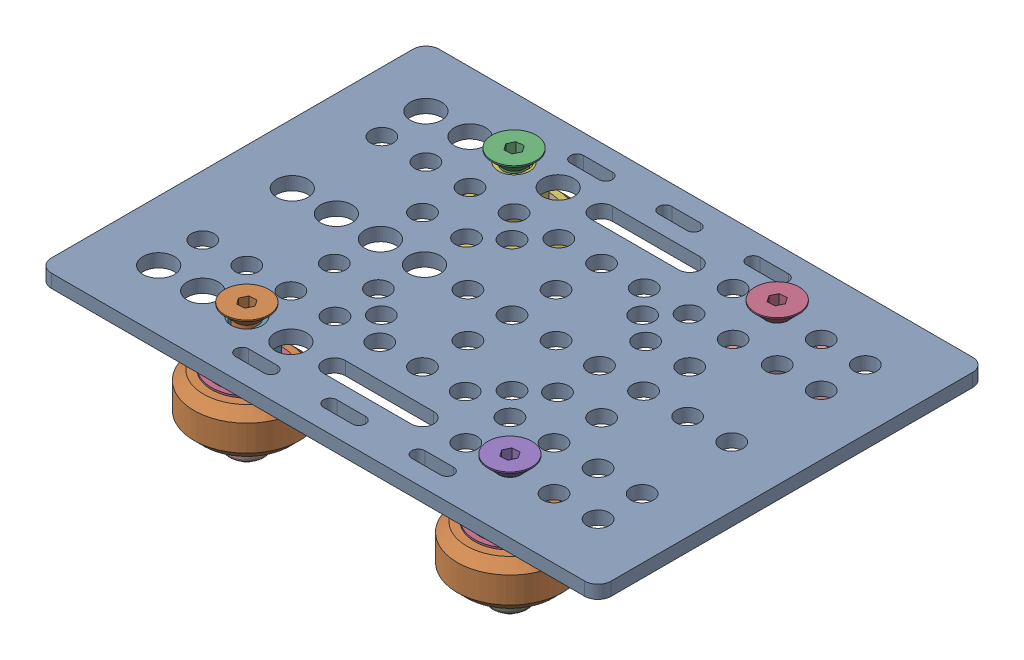
SolidWorks assembly plateau_haut, configuration Default. Lengths in mm.
Overall size (127 30 88.17).
37 component instances, 9 part files, 40 mates.
Components (placement in the parent):
- User Library-GANTRY-PLATE-127-88-1: User Library-GANTRY-PLATE-127-88 [Default] at (-22.0656 -4.5834 13.7385) size (127 3 88)
- item_8000118_vis_fhc_m5x30_din_7991_details_3-1: item_8000118_vis_fhc_m5x30_din_7991_details_3 [Default] at (-51.9156 -1.5834 44.0585) x (0.566406 0 0.824126) z (0 1 0) size (10 10 30)
- item_8000118_vis_fhc_m5x30_din_7991_details_3-2: item_8000118_vis_fhc_m5x30_din_7991_details_3 [Default] at (-51.9156 -1.5834 -16.5815) x (0.566406 0 0.824126) z (0 1 0) size (10 10 30)
- item_8000118_vis_fhc_m5x30_din_7991_details_3-3: item_8000118_vis_fhc_m5x30_din_7991_details_3 [Default] at (7.7844 -1.5834 -16.5815) x (0.566406 0 0.824126) z (0 1 0) size (10 10 30)
- item_8000118_vis_fhc_m5x30_din_7991_details_3-4: item_8000118_vis_fhc_m5x30_din_7991_details_3 [Default] at (7.7844 -1.5834 44.0585) x (0.566406 0 0.824126) z (0 1 0) size (10 10 30)
- User Library-ENTR-EXC-HEX10-6-1: User Library-ENTR-EXC-HEX10-6 [Défaut] at (-51.9156 -4.5834 -16.5815) x (0.999657 0 0.026177) z (0.026177 0 -0.999657) size (11.55 8.5 10)
- User Library-ENTR-EXC-HEX10-6-2: User Library-ENTR-EXC-HEX10-6 [Défaut] at (-51.9156 -4.5834 44.0585) x (-0.99999 0 -0.004471) z (-0.004471 0 0.99999) size (11.55 8.5 10)
- entretoise-1: entretoise [Default] at (7.7844 -10.5834 -16.5815) x (1 0 0) z (0 1 0) size (10 10 6)
- entretoise-2: entretoise [Default] at (7.7844 -10.5834 44.0585) x (1 0 0) z (0 1 0) size (10 10 6)
- rondelle-1: rondelle [Default] at (-51.9156 -11.5834 -16.5815) x (0.930418 0 -0.366501) z (0 1 0) size (8 8 1)
- rondelle-2: rondelle [Default] at (-51.9156 -11.5834 44.0585) x (1 0 0) z (0 1 0) size (8 8 1)
- rondelle-3: rondelle [Default] at (7.7844 -11.5834 -16.5815) x (1 0 0) z (0 1 0) size (8 8 1)
- rondelle-4: rondelle [Default] at (7.7844 -11.5834 44.0585) x (1 0 0) z (0 1 0) size (8 8 1)
- User Library-WHL-VSLOT-DLRN-1: User Library-WHL-VSLOT-DLRN [Straight] at (-51.9156 -17.0834 44.0585) x (0.999713 0 0.023977) z (-0.023977 0 0.999713) size (23.9 11 23.9)
  - User Library-WHL-VSLOT-DLRN_Solid V Wheel-1: User Library-WHL-VSLOT-DLRN_Solid V Wheel [Default] x (0 -1 0) z (0 0 1) size (10.2 23.9 23.9)
  - User Library-WHL-VSLOT-DLRN_Ball Bearing 5 x 16 x 5-1: User Library-WHL-VSLOT-DLRN_Ball Bearing 5 x 16 x 5 [Default] at (0 -3 0) x (0 -1 0) z (0.990411 0 0.138155) size (5 16 16)
  - User Library-WHL-VSLOT-DLRN_Ball Bearing 5 x 16 x 5-2: User Library-WHL-VSLOT-DLRN_Ball Bearing 5 x 16 x 5 [Default] at (0 3 0) x (0 1 0) z (-0.887666 0 -0.460488) size (5 16 16)
  - User Library-WHL-VSLOT-DLRN_Precision Shim 10 x 5 x 1-1: User Library-WHL-VSLOT-DLRN_Precision Shim 10 x 5 x 1 [Default] at (0 -0.5 0) x (0.977063 0 -0.212952) z (0.212952 0 0.977063) size (10 1 10)
- User Library-WHL-VSLOT-DLRN-2: User Library-WHL-VSLOT-DLRN [Straight] at (-51.9156 -17.0834 -16.5815) x (0.998521 0 0.054369) z (-0.054369 0 0.998521) size (23.9 11 23.9)
  - User Library-WHL-VSLOT-DLRN_Solid V Wheel-1: User Library-WHL-VSLOT-DLRN_Solid V Wheel [Default] x (0 -1 0) z (0 0 1) size (10.2 23.9 23.9)
  - User Library-WHL-VSLOT-DLRN_Ball Bearing 5 x 16 x 5-1: User Library-WHL-VSLOT-DLRN_Ball Bearing 5 x 16 x 5 [Default] at (0 -3 0) x (0 -1 0) z (0.990411 0 0.138155) size (5 16 16)
  - User Library-WHL-VSLOT-DLRN_Ball Bearing 5 x 16 x 5-2: User Library-WHL-VSLOT-DLRN_Ball Bearing 5 x 16 x 5 [Default] at (0 3 0) x (0 1 0) z (-0.887666 0 -0.460488) size (5 16 16)
  - User Library-WHL-VSLOT-DLRN_Precision Shim 10 x 5 x 1-1: User Library-WHL-VSLOT-DLRN_Precision Shim 10 x 5 x 1 [Default] at (0 -0.5 0) x (0.977063 0 -0.212952) z (0.212952 0 0.977063) size (10 1 10)
- User Library-WHL-VSLOT-DLRN-3: User Library-WHL-VSLOT-DLRN [Straight] at (7.7844 -17.0834 -16.5815) x (0.990448 0 -0.137886) z (0.137886 0 0.990448) size (23.9 11 23.9)
  - User Library-WHL-VSLOT-DLRN_Solid V Wheel-1: User Library-WHL-VSLOT-DLRN_Solid V Wheel [Default] x (0 -1 0) z (0 0 1) size (10.2 23.9 23.9)
  - User Library-WHL-VSLOT-DLRN_Ball Bearing 5 x 16 x 5-1: User Library-WHL-VSLOT-DLRN_Ball Bearing 5 x 16 x 5 [Default] at (0 -3 0) x (0 -1 0) z (0.990411 0 0.138155) size (5 16 16)
  - User Library-WHL-VSLOT-DLRN_Ball Bearing 5 x 16 x 5-2: User Library-WHL-VSLOT-DLRN_Ball Bearing 5 x 16 x 5 [Default] at (0 3 0) x (0 1 0) z (-0.887666 0 -0.460488) size (5 16 16)
  - User Library-WHL-VSLOT-DLRN_Precision Shim 10 x 5 x 1-1: User Library-WHL-VSLOT-DLRN_Precision Shim 10 x 5 x 1 [Default] at (0 -0.5 0) x (0.977063 0 -0.212952) z (0.212952 0 0.977063) size (10 1 10)
- User Library-WHL-VSLOT-DLRN-5: User Library-WHL-VSLOT-DLRN [Straight] at (7.7844 -17.0834 44.0585) x (0.984743 0 -0.174014) z (0.174014 0 0.984743) size (23.9 11 23.9)
  - User Library-WHL-VSLOT-DLRN_Solid V Wheel-1: User Library-WHL-VSLOT-DLRN_Solid V Wheel [Default] x (0 -1 0) z (0 0 1) size (10.2 23.9 23.9)
  - User Library-WHL-VSLOT-DLRN_Ball Bearing 5 x 16 x 5-1: User Library-WHL-VSLOT-DLRN_Ball Bearing 5 x 16 x 5 [Default] at (0 -3 0) x (0 -1 0) z (0.990411 0 0.138155) size (5 16 16)
  - User Library-WHL-VSLOT-DLRN_Ball Bearing 5 x 16 x 5-2: User Library-WHL-VSLOT-DLRN_Ball Bearing 5 x 16 x 5 [Default] at (0 3 0) x (0 1 0) z (-0.887666 0 -0.460488) size (5 16 16)
  - User Library-WHL-VSLOT-DLRN_Precision Shim 10 x 5 x 1-1: User Library-WHL-VSLOT-DLRN_Precision Shim 10 x 5 x 1 [Default] at (0 -0.5 0) x (0.977063 0 -0.212952) z (0.212952 0 0.977063) size (10 1 10)
- ecrou_frein2-1: ecrou_frein2 [Default] at (-51.9156 -22.5834 -16.5815) x (0 -1 0) z (0 0 1) size (5 9.24 8.1)
- ecrou_frein2-2: ecrou_frein2 [Default] at (7.7844 -22.5834 -16.5815) x (0 -1 0) z (0 0 1) size (5 9.24 8.1)
- ecrou_frein2-3: ecrou_frein2 [Default] at (-51.9156 -22.5834 44.0585) x (0 -1 0) z (0 0 1) size (5 9.24 8.1)
- ecrou_frein2-4: ecrou_frein2 [Default] at (7.7844 -22.5834 44.0585) x (0 -1 0) z (0 0 1) size (5 9.24 8.1)
Mates (geometry in assembly coordinates):
- Concentric1: concentric anti-aligned: cylinder of User Library-GANTRY-PLATE-127-88-1 through (-51.9156 -1.5834 44.0585) axis (0 -1 0) radius 3.55; cylinder of item_8000118_vis_fhc_m5x30_din_7991_details_3-1 through (-51.9156 -13.7834 44.0585) axis (0 1 0) radius 2.5
- Tangent2: tangent: plane of User Library-GANTRY-PLATE-127-88-1 through (-82.5656 -1.5834 54.7385) normal (0 1 0); circle of item_8000118_vis_fhc_m5x30_din_7991_details_3-1
- Concentric3: concentric anti-aligned: cylinder of User Library-GANTRY-PLATE-127-88-1 through (-51.9156 -1.5834 -16.5815) axis (0 -1 0) radius 3.55; cylinder of item_8000118_vis_fhc_m5x30_din_7991_details_3-2 through (-51.9156 -13.7834 -16.5815) axis (0 1 0) radius 2.5
- Coincident1: coincident anti-aligned: plane of User Library-GANTRY-PLATE-127-88-1 through (-82.5656 -1.5834 54.7385) normal (0 1 0); circle of item_8000118_vis_fhc_m5x30_din_7991_details_3-2
- Concentric4: concentric anti-aligned: cylinder of User Library-GANTRY-PLATE-127-88-1 through (7.7844 -1.5834 -16.5815) axis (0 -1 0) radius 2.55; cylinder of item_8000118_vis_fhc_m5x30_din_7991_details_3-3 through (7.7844 -13.7834 -16.5815) axis (0 1 0) radius 2.5
- Coincident2: coincident anti-aligned: plane of User Library-GANTRY-PLATE-127-88-1 through (-82.5656 -1.5834 54.7385) normal (0 1 0); circle of item_8000118_vis_fhc_m5x30_din_7991_details_3-3
- Concentric5: concentric anti-aligned: cylinder of User Library-GANTRY-PLATE-127-88-1 through (7.7844 -1.5834 44.0585) axis (0 -1 0) radius 2.55; cylinder of item_8000118_vis_fhc_m5x30_din_7991_details_3-4 through (7.7844 -13.7834 44.0585) axis (0 1 0) radius 2.5
- Coincident3: coincident anti-aligned: plane of User Library-GANTRY-PLATE-127-88-1 through (-82.5656 -1.5834 54.7385) normal (0 1 0); circle of item_8000118_vis_fhc_m5x30_din_7991_details_3-4
- Concentric6: concentric aligned: cylinder of User Library-GANTRY-PLATE-127-88-1 through (-51.9156 -1.5834 -16.5815) axis (0 -1 0) radius 3.55; cylinder of User Library-ENTR-EXC-HEX10-6-1 through (-51.9156 -2.0834 -16.5815) axis (0 -1 0) radius 3.555
- Coincident4: coincident anti-aligned: plane of User Library-GANTRY-PLATE-127-88-1 through (-82.5656 -4.5834 54.7385) normal (0 -1 0); plane of User Library-ENTR-EXC-HEX10-6-1 through (-51.9156 -4.5834 -16.5815) normal (0 1 0)
- Concentric7: concentric aligned: cylinder of User Library-GANTRY-PLATE-127-88-1 through (-51.9156 -1.5834 44.0585) axis (0 -1 0) radius 3.55; cylinder of User Library-ENTR-EXC-HEX10-6-2 through (-51.9156 -2.0834 44.0585) axis (0 -1 0) radius 3.555
- Coincident5: coincident anti-aligned: plane of User Library-GANTRY-PLATE-127-88-1 through (-82.5656 -4.5834 54.7385) normal (0 -1 0); plane of User Library-ENTR-EXC-HEX10-6-2 through (-51.9156 -4.5834 44.0585) normal (0 1 0)
- Concentric8: concentric anti-aligned: cylinder of item_8000118_vis_fhc_m5x30_din_7991_details_3-3 through (7.7844 -13.7834 -16.5815) axis (0 1 0) radius 2.5; cylinder of entretoise-1 through (7.7844 -4.5834 -16.5815) axis (0 -1 0) radius 2.5
- Coincident6: coincident anti-aligned: plane of User Library-GANTRY-PLATE-127-88-1 through (-82.5656 -4.5834 54.7385) normal (0 -1 0); plane of entretoise-1 through (7.7844 -4.5834 -16.5815) normal (0 1 0)
- Concentric9: concentric anti-aligned: cylinder of item_8000118_vis_fhc_m5x30_din_7991_details_3-4 through (7.7844 -13.7834 44.0585) axis (0 1 0) radius 2.5; cylinder of entretoise-2 through (7.7844 -4.5834 44.0585) axis (0 -1 0) radius 2.5
- Coincident7: coincident anti-aligned: plane of User Library-GANTRY-PLATE-127-88-1 through (-82.5656 -4.5834 54.7385) normal (0 -1 0); plane of entretoise-2 through (7.7844 -4.5834 44.0585) normal (0 1 0)
- Concentric10: concentric anti-aligned: cylinder of item_8000118_vis_fhc_m5x30_din_7991_details_3-2 through (-51.9156 -13.7834 -16.5815) axis (0 1 0) radius 2.5; cylinder of rondelle-1 through (-51.9156 -10.5834 -16.5815) axis (0 -1 0) radius 2.5
- Concentric11: concentric anti-aligned: cylinder of item_8000118_vis_fhc_m5x30_din_7991_details_3-1 through (-51.9156 -13.7834 44.0585) axis (0 1 0) radius 2.5; cylinder of rondelle-2 through (-51.9156 -10.5834 44.0585) axis (0 -1 0) radius 2.5
- Concentric12: concentric anti-aligned: cylinder of item_8000118_vis_fhc_m5x30_din_7991_details_3-4 through (7.7844 -13.7834 44.0585) axis (0 1 0) radius 2.5; cylinder of rondelle-4 through (7.7844 -10.5834 44.0585) axis (0 -1 0) radius 2.5
- Concentric13: concentric anti-aligned: cylinder of item_8000118_vis_fhc_m5x30_din_7991_details_3-3 through (7.7844 -13.7834 -16.5815) axis (0 1 0) radius 2.5; cylinder of rondelle-3 through (7.7844 -10.5834 -16.5815) axis (0 -1 0) radius 2.5
- Coincident8: coincident anti-aligned: plane of User Library-ENTR-EXC-HEX10-6-1 through (-51.9156 -10.5834 -16.5815) normal (0 -1 0); plane of rondelle-1 through (-51.9156 -10.5834 -16.5815) normal (0 1 0)
- Coincident9: coincident anti-aligned: plane of User Library-ENTR-EXC-HEX10-6-2 through (-51.9156 -10.5834 44.0585) normal (0 -1 0); plane of rondelle-2 through (-51.9156 -10.5834 44.0585) normal (0 1 0)
- Coincident10: coincident anti-aligned: plane of entretoise-1 through (7.7844 -10.5834 -16.5815) normal (0 -1 0); plane of rondelle-3 through (7.7844 -10.5834 -16.5815) normal (0 1 0)
- Coincident11: coincident anti-aligned: plane of entretoise-2 through (7.7844 -10.5834 44.0585) normal (0 -1 0); plane of rondelle-4 through (7.7844 -10.5834 44.0585) normal (0 1 0)
- Concentric14: concentric anti-aligned: cylinder of item_8000118_vis_fhc_m5x30_din_7991_details_3-2 through (-51.9156 -13.7834 -16.5815) axis (0 1 0) radius 2.5; cylinder of User Library-WHL-VSLOT-DLRN-2/User Library-WHL-VSLOT-DLRN_Ball Bearing 5 x 16 x 5-1 through (-51.9156 -20.0834 -16.5815) axis (0 -1 0) radius 2.5
- Concentric15: concentric anti-aligned: cylinder of item_8000118_vis_fhc_m5x30_din_7991_details_3-1 through (-51.9156 -13.7834 44.0585) axis (0 1 0) radius 2.5; cylinder of User Library-WHL-VSLOT-DLRN-1/User Library-WHL-VSLOT-DLRN_Ball Bearing 5 x 16 x 5-1 through (-51.9156 -20.0834 44.0585) axis (0 -1 0) radius 2.5
- Concentric16: concentric anti-aligned: cylinder of item_8000118_vis_fhc_m5x30_din_7991_details_3-4 through (7.7844 -13.7834 44.0585) axis (0 1 0) radius 2.5; cylinder of User Library-WHL-VSLOT-DLRN-5/User Library-WHL-VSLOT-DLRN_Ball Bearing 5 x 16 x 5-1 through (7.7844 -20.0834 44.0585) axis (0 -1 0) radius 2.5
- Concentric17: concentric anti-aligned: cylinder of item_8000118_vis_fhc_m5x30_din_7991_details_3-3 through (7.7844 -13.7834 -16.5815) axis (0 1 0) radius 2.5; cylinder of User Library-WHL-VSLOT-DLRN-3/User Library-WHL-VSLOT-DLRN_Ball Bearing 5 x 16 x 5-1 through (7.7844 -20.0834 -16.5815) axis (0 -1 0) radius 2.5
- Coincident12: coincident anti-aligned: plane of rondelle-1 through (-51.9156 -11.5834 -16.5815) normal (0 -1 0); plane of User Library-WHL-VSLOT-DLRN-2/User Library-WHL-VSLOT-DLRN_Ball Bearing 5 x 16 x 5-2 through (-50.6454 -11.5834 -18.7348) normal (0 1 0)
- Coincident13: coincident anti-aligned: plane of rondelle-2 through (-51.9156 -11.5834 44.0585) normal (0 -1 0); plane of User Library-WHL-VSLOT-DLRN-1/User Library-WHL-VSLOT-DLRN_Ball Bearing 5 x 16 x 5-2 through (-50.7115 -11.5834 41.8676) normal (0 1 0)
- Coincident14: coincident anti-aligned: plane of rondelle-4 through (7.7844 -11.5834 44.0585) normal (0 -1 0); plane of User Library-WHL-VSLOT-DLRN-5/User Library-WHL-VSLOT-DLRN_Ball Bearing 5 x 16 x 5-2 through (8.5319 -11.5834 41.6729) normal (0 1 0)
- Coincident15: coincident anti-aligned: plane of rondelle-3 through (7.7844 -11.5834 -16.5815) normal (0 -1 0); plane of User Library-WHL-VSLOT-DLRN-3/User Library-WHL-VSLOT-DLRN_Ball Bearing 5 x 16 x 5-2 through (8.6187 -11.5834 -18.9382) normal (0 1 0)
- Concentric19: concentric aligned: cylinder of item_8000118_vis_fhc_m5x30_din_7991_details_3-2 through (-51.9156 -13.7834 -16.5815) axis (0 1 0) radius 2.5; cylinder of ecrou_frein2-1 through (-51.9156 -27.5834 -16.5815) axis (0 1 0) radius 2.067
- Concentric20: concentric aligned: cylinder of item_8000118_vis_fhc_m5x30_din_7991_details_3-1 through (-51.9156 -13.7834 44.0585) axis (0 1 0) radius 2.5; cylinder of ecrou_frein2-3 through (-51.9156 -27.5834 44.0585) axis (0 1 0) radius 2.067
- Concentric21: concentric aligned: cylinder of item_8000118_vis_fhc_m5x30_din_7991_details_3-3 through (7.7844 -13.7834 -16.5815) axis (0 1 0) radius 2.5; cylinder of ecrou_frein2-2 through (7.7844 -27.5834 -16.5815) axis (0 1 0) radius 2.067
- Concentric22: concentric aligned: cylinder of item_8000118_vis_fhc_m5x30_din_7991_details_3-4 through (7.7844 -13.7834 44.0585) axis (0 1 0) radius 2.5; cylinder of ecrou_frein2-4 through (7.7844 -27.5834 44.0585) axis (0 1 0) radius 2.067
- Coincident16: coincident anti-aligned: plane of User Library-WHL-VSLOT-DLRN-1/User Library-WHL-VSLOT-DLRN_Ball Bearing 5 x 16 x 5-1 through (-51.5109 -22.5834 41.5915) normal (0 -1 0); plane of ecrou_frein2-3 through (-48.4781 -22.5834 44.0585) normal (0 1 0)
- Coincident17: coincident anti-aligned: plane of User Library-WHL-VSLOT-DLRN-2/User Library-WHL-VSLOT-DLRN_Ball Bearing 5 x 16 x 5-1 through (-51.4361 -22.5834 -19.0351) normal (0 -1 0); plane of ecrou_frein2-1 through (-48.4781 -22.5834 -16.5815) normal (0 1 0)
- Coincident18: coincident anti-aligned: plane of User Library-WHL-VSLOT-DLRN-3/User Library-WHL-VSLOT-DLRN_Ball Bearing 5 x 16 x 5-1 through (7.7851 -22.5834 -19.0815) normal (0 -1 0); plane of ecrou_frein2-2 through (11.2219 -22.5834 -16.5815) normal (0 1 0)
- Coincident19: coincident anti-aligned: plane of User Library-WHL-VSLOT-DLRN-5/User Library-WHL-VSLOT-DLRN_Ball Bearing 5 x 16 x 5-1 through (7.6937 -22.5834 41.5602) normal (0 -1 0); plane of ecrou_frein2-4 through (11.2219 -22.5834 44.0585) normal (0 1 0)
